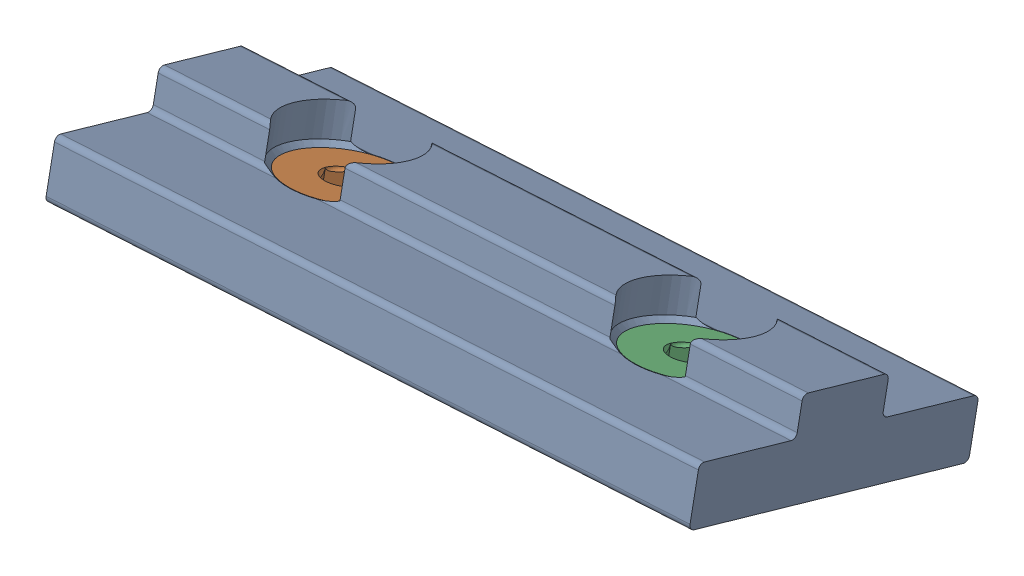
SolidWorks assembly 8020-6760_676009 3649 assem, configuration Default. Lengths in mm.
Overall size (48.13 14.83 21.87).
3 component instances, 2 part files, 5 mates.
Components (placement in the parent):
- 8020-6760_670509-1: 8020-6760_670509 [Default] at (-86.2648 880.0126 340.9831) x (0.060835 -0.963374 0.261171) z (0.99788 0.064763 0.006453) size (6.35 20.62 47.37)
- 8020-6760_3649-LT-1: 8020-6760_3649-LT [Default] at (-5.8282 -13.742 3.2541) x (0.998115 0.060835 -0.008092) z (-0.008092 0.261171 0.965259) size (7.62 6.41 7.62)
- 8020-6760_3649-LT-2: 8020-6760_3649-LT [Default] at (19.518 -12.097 3.418) x (0.998115 0.060835 -0.008092) z (-0.008092 0.261171 0.965259) size (7.62 6.41 7.62)
Mates (geometry in assembly coordinates):
- Concentric1: concentric aligned: cylinder of 8020-6760_670509-1 through (8.9322 9.046 -2.3914) axis (-0.060835 0.963374 -0.261171) radius 2.2479; cylinder of 8020-6760_3649-LT-2 through (9.0867 6.599 -1.728) axis (-0.060835 0.963374 -0.261171) radius 2.0828
- Concentric2: concentric aligned: circle of 8020-6760_670509-1; circle of 8020-6760_3649-LT-2
- Coincident1: coincident aligned: plane of 8020-6760_670509-1 through (20.2914 4.7269 -11.2435) normal (-0.060835 0.963374 -0.261171); plane of 8020-6760_3649-LT-2 through (9.0867 6.599 -1.728) normal (-0.060835 0.963374 -0.261171)
- Concentric3: concentric aligned: cylinder of 8020-6760_670509-1 through (-16.4139 7.401 -2.5553) axis (-0.060835 0.963374 -0.261171) radius 2.2479; circle of 8020-6760_3649-LT-1
- Coincident2: coincident aligned: plane of 8020-6760_670509-1 through (20.2914 4.7269 -11.2435) normal (-0.060835 0.963374 -0.261171); plane of 8020-6760_3649-LT-1 through (-16.2594 4.954 -1.8919) normal (-0.060835 0.963374 -0.261171)
